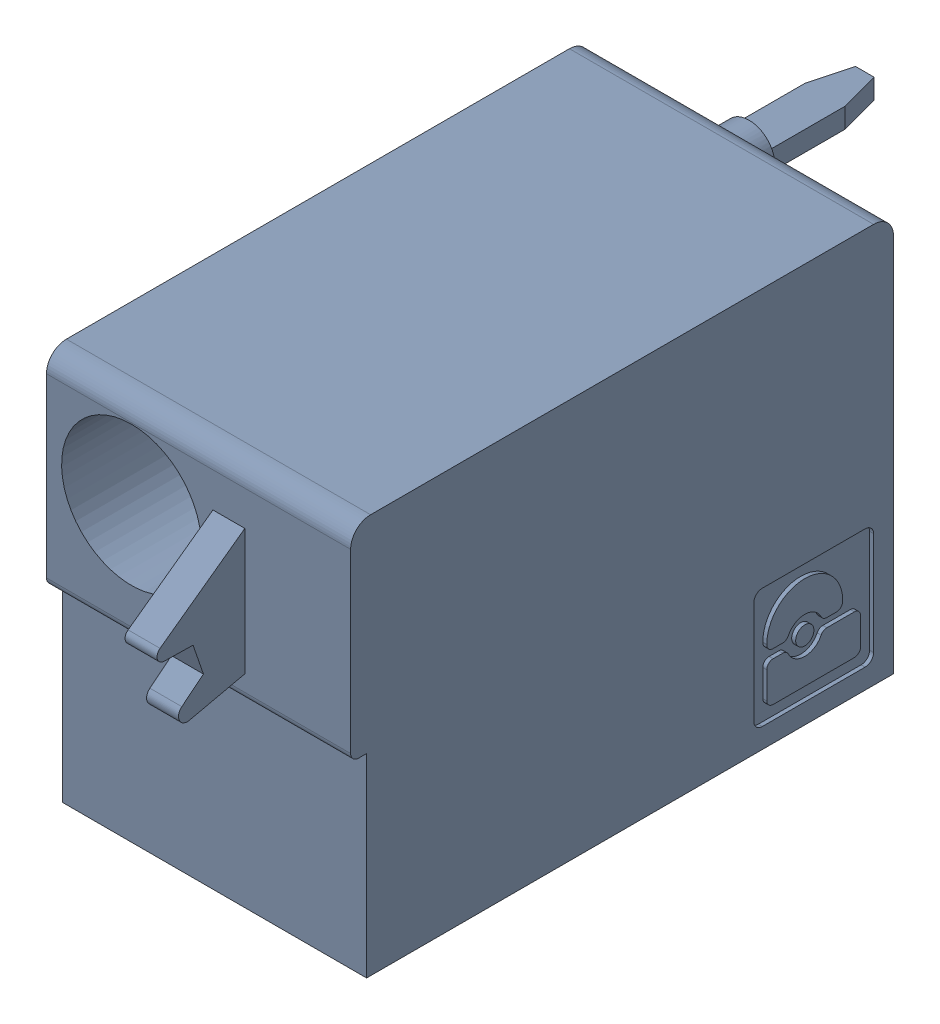
SolidWorks assembly J57, configuration Default. Lengths in mm.
Overall size (7.62 10 19.2).
2 component instances, 1 part files, 0 mates.
Components (placement in the parent):
- 1790487-1: 1790487 [Default] at (160.425 -5.67 -10.6) x (0 1 0) z (1 0 0) size (10 19.2 7.62)
  - ffkdsa1-v2-7.62-1: ffkdsa1-v2-7.62 [Default] at (-15.6914 -27.508 9.12) x (0 -1 0) z (0 0 1) size (19.2 10 7.62)
